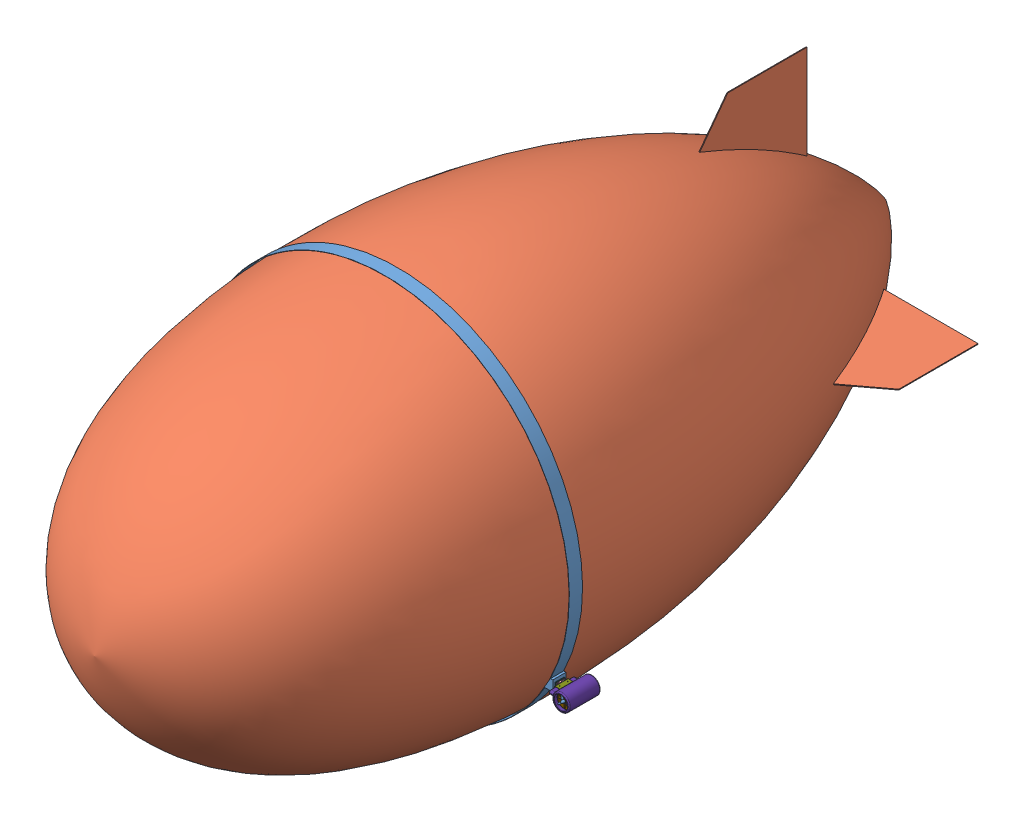
SolidWorks assembly BLIMP, configuration Default. Lengths in mm.
Overall size (1876.01 1876.01 3000).
45 component instances, 20 part files, 18 mates.
Components (placement in the parent):
- COPOLING_RING-1: COPOLING_RING [Default] at origin size (1402 1402 50)
  - estrutura de acopolamento-1: estrutura de acopolamento [Default] at origin size (1402 1402 50)
- envelope-1: envelope [Default] at (0 0 1100) size (1876.01 1876.01 3000)
- GONDOLA-1: GONDOLA [Default] at (0 -700 70) size (139.38 110.34 205.99)
  - gondola-1: gondola [Default] at origin size (139.38 85.01 205.99)
  - Towerpro mg16r-1: Towerpro mg16r [Default] at (-49.3349 -85.5863 -106.4276) x (0 0 -1) z (0 -1 0) size (33 30 12)
  - perno monobraco servo-1: perno monobraco servo [Default] at (-23.3349 -77 -105.8) x (0 0.120221 -0.992747) z (0 -0.992747 -0.120221) size (41 5.7 8)
  - apoio_camera-1: apoio_camera [Default] at (-17.6349 -59.5495 -83.5406) x (1 0 0) z (0 -0.120221 0.992747) size (30 50 40)
  - LV-EZ0-1: LV-EZ0 [Default] at (-4.2742 -97.0513 -90.4971) x (1 0 0) z (0 0.992747 0.120221) size (19.9 16.44 22.1)
    - LV-EZ0_4-1: LV-EZ0_4 [Default] at (1.6393 -0.3975 -0.4339) size (19.9 1.25 22.1)
    - LV-EZ0_1-1: LV-EZ0_1 [Default] at (-8.2207 0.2775 6.3761) size (1.5 1.15 1.5)
    - LV-EZ0_2-1: LV-EZ0_2 [Default] at (-8.2207 0.2775 8.9161) size (1.5 1.15 1.5)
    - LV-EZ0_3-1: LV-EZ0_3 [Default] at (-4.6707 0.2775 -8.9339) size (4 1.15 4)
    - LV-EZ0_5-1: LV-EZ0_5 [Default] at (1.6393 -0.8975 -0.4339) x (1 0 0) z (0 0 -1) size (15.5 15.81 15.5)
    - LV-EZ0_6-1: LV-EZ0_6 [Default] at (1.6393 0.2275 -0.4339) x (-1 0 0) z (0 0 1) size (11 5 11)
    - LV-EZ0_7-1: LV-EZ0_7 [Default] at (1.6393 -3.7725 -0.4339) x (-1 0 0) z (0 0 1) size (8.56 2.06 8.56)
    - LV-EZ0_1-3: LV-EZ0_1 [Default] at (-8.2207 0.2775 3.8361) size (1.5 1.15 1.5)
    - LV-EZ0_1-5: LV-EZ0_1 [Default] at (-8.2207 0.2775 1.2961) size (1.5 1.15 1.5)
    - LV-EZ0_1-7: LV-EZ0_1 [Default] at (-8.2207 0.2775 -1.2439) size (1.5 1.15 1.5)
    - LV-EZ0_1-9: LV-EZ0_1 [Default] at (-8.2207 0.2775 -3.7839) size (1.5 1.15 1.5)
    - LV-EZ0_3-3: LV-EZ0_3 [Default] at (7.9293 0.2775 8.0661) size (4 1.15 4)
    - LV-EZ0_1-13: LV-EZ0_1 [Default] at (-8.2207 0.2775 -6.3239) size (1.5 1.15 1.5)
  - camera-1: camera [Default] at (-2.6349 -72.2767 -103.2134) x (0 -0.992747 -0.120221) z (0 -0.120221 0.992747) size (21 26 23)
- MOTOR-4: MOTOR [Default] at (620.9474 -322.8399 -36.5879) x (1 0 0) z (0 0 -1) size (119.7 66.56 119.6)
  - Towerpro mg16r-1: Towerpro mg16r [Default] at (0 -2.5863 -17.6276) x (0 0 -1) z (0 -1 0) size (33 30 12)
  - servo_base-1: servo_base [Default] at (17 14 -29) x (1 0 0) z (0 0 -1) size (3 16 35)
  - perno monobraco servo-1: perno monobraco servo [Default] at (27 6 -17) x (0 0.002714 -0.999996) z (0 -0.999996 -0.002714) size (41 5.7 8)
  - fixacao_motores-1: fixacao_motores [Default] at (29 14.5064 7.9978) x (1 0 0) z (0 -0.000256 -1) size (20 17 50)
  - propeller-1: propeller [Default] at (87.2 5.9848 -76.5) x (-1 0 0) z (0 -0.000256 -1) size (87 65 119)
  - fan_grid-1: fan_grid [Default] at (87.2 5.9898 -57) x (1 0 0) z (0 0.000256 1) size (51 51 15)
  - fan-1: fan [Default] at (87.2 5.9876 -65.5) x (-0.687606 -0.726084 0.000186) z (0 -0.000256 -1) size (46.5 40.08 12.02)
  - motor-1: motor [Default] at (87.2 5.9955 -34.5) x (1 0 0) z (0 -0.000256 -1) size (10.6 10.6 38)
- MOTOR-3: MOTOR [Default] at (-620.9474 -334.8399 -36.5879) x (-1 0 0) z (0 0 -1) size (119.7 66.56 119.6)
  - Towerpro mg16r-1: Towerpro mg16r [Default] at (0 -2.5863 -17.6276) x (0 0 -1) z (0 -1 0) size (33 30 12)
  - servo_base-1: servo_base [Default] at (17 14 -29) x (1 0 0) z (0 0 -1) size (3 16 35)
  - perno monobraco servo-1: perno monobraco servo [Default] at (27 6 -17) x (0 0.002714 -0.999996) z (0 -0.999996 -0.002714) size (41 5.7 8)
  - fixacao_motores-1: fixacao_motores [Default] at (29 14.5064 7.9978) x (1 0 0) z (0 -0.000256 -1) size (20 17 50)
  - propeller-1: propeller [Default] at (87.2 5.9848 -76.5) x (-1 0 0) z (0 -0.000256 -1) size (87 65 119)
  - fan_grid-1: fan_grid [Default] at (87.2 5.9898 -57) x (1 0 0) z (0 0.000256 1) size (51 51 15)
  - fan-1: fan [Default] at (87.2 5.9876 -65.5) x (-0.687606 -0.726084 0.000186) z (0 -0.000256 -1) size (46.5 40.08 12.02)
  - motor-1: motor [Default] at (87.2 5.9955 -34.5) x (1 0 0) z (0 -0.000256 -1) size (10.6 10.6 38)
- FAN-3: FAN [Default] at (-55.9985 -536.0043 -1587.2) x (0 0 1) z (-1 -0.000256 0) size (61.07 61.32 42.6)
  - fan_grid-1: fan_grid [Default] at (87.2 5.9898 -57) x (1 0 0) z (0 0.000256 1) size (51 51 15)
  - fan-1: fan [Default] at (87.2 5.9876 -65.5) x (-0.687606 -0.726084 0.000186) z (0 -0.000256 -1) size (46.5 40.08 12.02)
  - motor-1: motor [Default] at (87.2 5.9955 -34.5) x (1 0 0) z (0 -0.000256 -1) size (10.6 10.6 38)
Mates (geometry in assembly coordinates):
- Coincident1: coincident aligned: plane of envelope-1 through (0 0 1100) normal (0 1 0); plane of assembly
- Coincident2: coincident aligned: plane of envelope-1 through (0 0 1100) normal (1 0 0); plane of assembly
- Coincident3: coincident aligned: plane of COPOLING_RING-1/estrutura de acopolamento-1 through (0 0 0) normal (0 1 0)
- Coincident4: coincident aligned: plane of COPOLING_RING-1/estrutura de acopolamento-1 through (0 0 0) normal (1 0 0)
- Distance1: distance = 1100 mm aligned: plane of assembly; plane of envelope-1 through (0 0 1100) normal (0 0 1)
- Coincident6: coincident aligned: plane of COPOLING_RING-1/estrutura de acopolamento-1 through (0 0 0) normal (0 0 1)
- Distance2: distance = 70 mm aligned: plane of GONDOLA-1/gondola-1 through (0 -700 70) normal (0 0 1)
- Coincident10: coincident aligned: plane of GONDOLA-1/gondola-1 through (0 -700 70) normal (1 0 0)
- Distance3: distance = 700 mm aligned: plane of GONDOLA-1/gondola-1 through (0 -700 70) normal (0 1 0)
- Coincident11: coincident anti-aligned: plane of MOTOR-4/servo_base-1 through (637.9474 -320.8399 -7.5879) normal (-1 0 0); plane of COPOLING_RING-1/estrutura de acopolamento-1 through (637.9474 -309 -50) normal (1 0 0)
- Concentric1: concentric aligned: cylinder of COPOLING_RING-1/estrutura de acopolamento-1 through (-862.0526 -328.8399 -10.3879) axis (1 0 0) radius 2.25; cylinder of MOTOR-4/Towerpro mg16r-1 through (637.9474 -328.8399 -10.3879) axis (1 0 0) radius 2
- Concentric2: concentric aligned: cylinder of COPOLING_RING-1/estrutura de acopolamento-1 through (-862.0526 -328.8399 -39.7879) axis (1 0 0) radius 2.25; cylinder of MOTOR-4/Towerpro mg16r-1 through (637.9474 -328.8399 -39.7879) axis (1 0 0) radius 2
- Coincident12: coincident anti-aligned: plane of COPOLING_RING-1/estrutura de acopolamento-1 through (-637.9474 -309 -50) normal (-1 0 0); plane of MOTOR-3/servo_base-1 through (-637.9474 -336.8399 -7.5879) normal (1 0 0)
- Concentric4: concentric anti-aligned: cylinder of COPOLING_RING-1/estrutura de acopolamento-1 through (-862.0526 -328.8399 -10.3879) axis (1 0 0) radius 2.25; cylinder of MOTOR-3/Towerpro mg16r-1 through (-637.9474 -328.8399 -10.3879) axis (-1 0 0) radius 2
- Concentric5: concentric anti-aligned: cylinder of COPOLING_RING-1/estrutura de acopolamento-1 through (-862.0526 -328.8399 -39.7879) axis (1 0 0) radius 2.25; cylinder of MOTOR-3/Towerpro mg16r-1 through (-637.9474 -328.8399 -39.7879) axis (-1 0 0) radius 2
- Concentric6: concentric anti-aligned: cylinder of envelope-1 through (-10 -530 -1500) axis (1 0 0) radius 25.5; cylinder of FAN-3/fan_grid-1 through (8.5 -530 -1500) axis (-1 0 0) radius 25.5
- Distance4: distance = 5 mm aligned: plane of FAN-3/fan_grid-1 through (-6.5 -530 -1500) normal (-1 0 0); plane of envelope-1 through (-1.5 -650 -1600) normal (-1 0 0)
- Parallel1: parallel aligned: plane of FAN-3/fan_grid-1 through (8.5 -529.5 -1524.795) normal (0 1 0); plane of assembly
